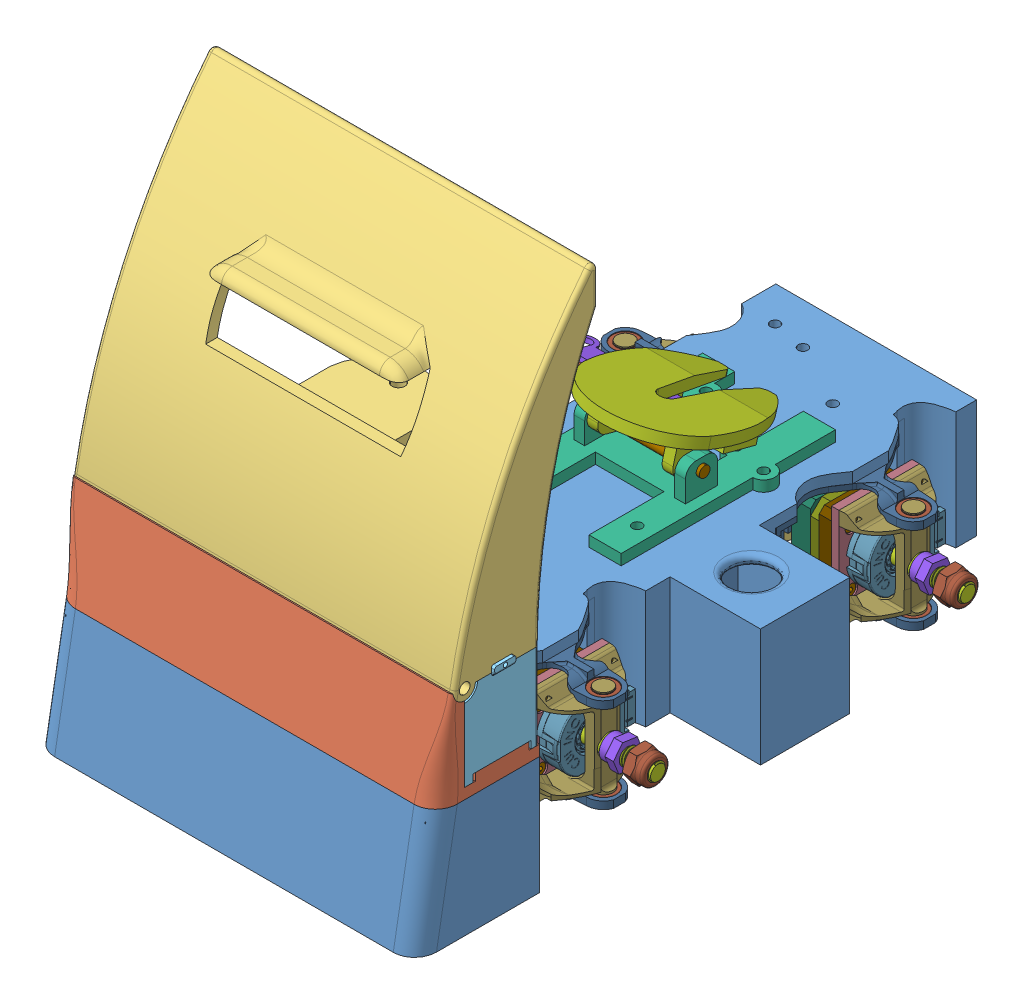
SolidWorks assembly Chassis assembly 3, configuration Default. Lengths in mm.
Overall size (185.37 241.94 304.3).
159 component instances, 30 part files, 30 mates.
Components (placement in the parent):
- Dolly chassis combined-2: Dolly chassis combined [Default] at (6.0852 69.6365 39.9835) x (1 0 0) z (0 1 0) size (178 304.3 55)
- front assembly 2-1: front assembly 2 [Default] at (-63.237 -3.2115 151.6894) size (181 187.95 83.28)
  - Foldable front base 2-1: Foldable front base 2 [Default] at (158.3211 77.8479 159.546) size (179.15 52.01 49.18)
  - foldable front flap 2-1: foldable front flap 2 [Default] at (69.3211 122.8479 151.0232) x (-1 0 0) z (0 0 -1) size (178.61 145.94 74.18)
  - Foldable front side flap right 2-1: Foldable front side flap right 2 [Default] at (-17.1789 86.3479 110.946) x (0 0 1) z (-1 0 0) size (35 43 8.5)
  - Foldable front side flap left 2-1: Foldable front side flap left 2 [Default] at (155.8211 86.3479 145.946) x (0 0 -1) z (1 0 0) size (35 43 8.5)
- Fifth_wheel_assembly-1: Fifth_wheel_assembly [Default] at (30.1809 28.8317 169.367) x (-1 0 0) z (0 0 -1) size (90.59 41.74 100)
  - Fifth_wheel_mount-1: Fifth_wheel_mount [Default] at (-6.9031 48.3048 102.7348) size (67.09 20 100)
  - Fifth_wheel_disk-1: Fifth_wheel_disk [Default] at (-5.9031 71.3457 44.4932) x (1 0 0) z (0 -0.255937 0.966694) size (66.74 23.06 75.99)
  - Fifth_wheel_kingpin-1: Fifth_wheel_kingpin [Default] at (-1.4031 62.5809 65.8769) x (1 0 0) z (0 -0.255937 0.966694) size (80 2 20)
  - Fifth_wheel_axle-1: Fifth_wheel_axle [Default] at (51.5969 60.8048 45.2348) x (0 0.948415 -0.31703) z (1 0 0) size (5 5 55)
- Module Assembly-2: Module Assembly [Default] at (72.5852 42.1365 211.1335) x (0 0 -1) z (1 0 0) size (68.25 51.28 97.81)
  - Housing-1: Housing [Default] at origin size (64.25 48.5 67.91)
  - Bearing 12x8-1: Bearing 12x8 [Default] at (0 -18.25 0.75) x (-0.914388 0 0.40484) z (-0.40484 0 -0.914388) size (12 3.5 12)
  - Spindle-1: Spindle [Default] at (0 2 0.75) size (49.04 45 20.5)
  - Spindle base-1: Spindle base [Default] at (0 2 -15.25) x (-1 0 0) z (0 -1 0) size (37.62 3.5 44.8)
  - Encoder-1: Encoder [Défaut] at (0 2 -12.48) x (0 1 0) z (0 0 1) size (28.68 37.25 10.4)
  - Wheel-1: Wheel [Default] at (0 2 -8.55) x (0.929787 0.368098 0) z (0.368098 -0.929787 0) size (81.5 31 81.5) (hidden)
  - Stepper Nema14-1: Stepper Nema14 [Predeterminado] at (4.764 -15.5 -30.1157) x (-1 0 0) z (0 1 0) size (37.8 40 35)
    - nema14_base-1: nema14_base [Predeterminado] at (-12.736 -8.6343 35) size (37.8 9 35)
    - nema14_centro-1: nema14_centro [Predeterminado] at (-12.736 0.3657 35) size (35 4 35)
    - nema14_eje-1: nema14_eje [Predeterminado] at (4.764 -6.6343 17.5) x (0 1 0) z (-0.939004 0 0.343907) size (38 5 5)
    - nema14_techo-1: nema14_techo [Predeterminado] at (-12.736 4.3657 35) size (35 9 35)
  - Servo motor-1: Servo motor [Default] at (-25.7048 26.288 -66.0832) x (0 0 1) z (1 0 0) size (11.5 29.2 32.5) (flexible)
    - TowerPro-SG90-Body-1: TowerPro-SG90-Body [Default] at (13.6721 7.288 30.7048) size (11.5 26 32.5)
    - ServoFinalGear-1: ServoFinalGear [Default] at (13.6721 33.288 25.7048) x (0.607544 0 -0.794286) z (0.794286 0 0.607544) size (4.64 3.2 4.64)
  - Control arm-1: Control arm [Default] at (0 -7.5 -52.4111) x (0.891007 0 0.45399) z (0.45399 0 -0.891007) size (37.9 4.5 7.8)
  - Ball joint assy-1: Ball joint assy [Default] at (-26.7302 -5 -12.8697) x (-0.874356 0 0.485286) z (0.485286 0 0.874356) size (15.43 16.21 22.24) (flexible)
    - Ball-1: Ball [Default] at origin size (5.5 15.11 5.5)
    - Joint-1: Joint [Default] at (-3.8823 13.66 -6.9948) x (0.874356 0 -0.485286) z (0 -1 0) size (5.1 22.6 5.1)
  - Ball joint assy-2: Ball joint assy [Default] at (-26.7302 -5 -66.0308) x (-0.846813 0 0.531891) z (0.531891 0 0.846813) size (16.34 16.21 21.85) (flexible)
    - Ball-1: Ball [Default] at origin size (5.5 15.11 5.5)
    - Joint-1: Joint [Default] at (4.2551 13.66 6.7745) x (-0.846813 0 0.531891) z (0 -1 0) size (5.1 22.6 5.1)
  - Steering rod-1: Steering rod [Default] at (-26.7302 -18.66 -18.4608) x (-0.014502 0.999895 0) z (-0.999895 -0.014502 0) size (3 28.27 3)
  - Wheel adapter-1: Wheel adapter [Default] at (0 2 -13.8175) x (0.291296 -0.956633 0) z (-0.956633 -0.291296 0) size (8.34 40 8.37)
  - Wheel spacer-1: Wheel spacer [Default] at (0 2 12.25) x (0.368098 -0.929787 0) z (0.929787 0.368098 0) size (13.86 8 12)
  - M3x5 din 7984-1: M3x5 din 7984 [Default] at (15.31 20.9 -16.25) x (0.933505 0.358563 0) z (0 0 -1) size (5.5 5.5 7)
  - Housing lid-1: Housing lid [Default] at (0 4 0) x (-1 0 0) z (0 0 1) size (68.25 9.28 69.91)
  - Bearing 12x8-3: Bearing 12x8 [Default] at (0 22.25 0.75) x (-0.914388 0 0.40484) z (0.40484 0 0.914388) size (12 3.5 12)
  - M8 nut-1: M8 nut [Default] at (0 2 16.6825) x (-0.817347 -0.576146 0) z (0 0 1) size (13 16.06 8.5)
  - M3x5 din 7984-2: M3x5 din 7984 [Default] at (15.31 -16.9 -16.25) x (-0.933505 0.358563 0) z (0 0 -1) size (5.5 5.5 7)
  - M3x5 din 7984-3: M3x5 din 7984 [Default] at (-15.31 20.9 -16.25) x (0.933505 -0.358563 0) z (0 0 -1) size (5.5 5.5 7)
  - M3x5 din 7984-4: M3x5 din 7984 [Default] at (-15.31 -16.9 -16.25) x (-0.933505 -0.358563 0) z (0 0 -1) size (5.5 5.5 7)
  - M3x5 din 7984-5: M3x5 din 7984 [Default] at (-13 15 -17.75) x (0.999849 0.017374 0) z (0 0 1) size (5.5 5.5 7)
  - M3x5 din 7984-6: M3x5 din 7984 [Default] at (-13 -11 -17.75) x (-0.999849 0.017374 0) z (0 0 1) size (5.5 5.5 7)
  - M3x5 din 7984-7: M3x5 din 7984 [Default] at (13 15 -17.75) x (0.999849 -0.017374 0) z (0 0 1) size (5.5 5.5 7)
  - M3x5 din 7984-8: M3x5 din 7984 [Default] at (13 -11 -17.75) x (-0.999849 -0.017374 0) z (0 0 1) size (5.5 5.5 7)
- Module Assembly-3: Module Assembly [Default] at (72.5852 42.1365 66.4835) x (0 0 -1) z (1 0 0) size (68.25 51.28 97.81)
  - Housing-1: Housing [Default] at origin size (64.25 48.5 67.91)
  - Bearing 12x8-1: Bearing 12x8 [Default] at (0 -18.25 0.75) x (-0.914388 0 0.40484) z (-0.40484 0 -0.914388) size (12 3.5 12)
  - Spindle-1: Spindle [Default] at (0 2 0.75) size (49.04 45 20.5)
  - Spindle base-1: Spindle base [Default] at (0 2 -15.25) x (-1 0 0) z (0 -1 0) size (37.62 3.5 44.8)
  - Encoder-1: Encoder [Défaut] at (0 2 -12.48) x (0 1 0) z (0 0 1) size (28.68 37.25 10.4)
  - Wheel-1: Wheel [Default] at (0 2 -8.55) x (0.929787 0.368098 0) z (0.368098 -0.929787 0) size (81.5 31 81.5) (hidden)
  - Stepper Nema14-1: Stepper Nema14 [Predeterminado] at (4.764 -15.5 -30.1157) x (-1 0 0) z (0 1 0) size (37.8 40 35)
    - nema14_base-1: nema14_base [Predeterminado] at (-12.736 -8.6343 35) size (37.8 9 35)
    - nema14_centro-1: nema14_centro [Predeterminado] at (-12.736 0.3657 35) size (35 4 35)
    - nema14_eje-1: nema14_eje [Predeterminado] at (4.764 -6.6343 17.5) x (0 1 0) z (-0.939004 0 0.343907) size (38 5 5)
    - nema14_techo-1: nema14_techo [Predeterminado] at (-12.736 4.3657 35) size (35 9 35)
  - Servo motor-1: Servo motor [Default] at (-25.7048 26.288 -66.0832) x (0 0 1) z (1 0 0) size (11.5 29.2 32.5) (flexible)
    - TowerPro-SG90-Body-1: TowerPro-SG90-Body [Default] at (13.6721 7.288 30.7048) size (11.5 26 32.5)
    - ServoFinalGear-1: ServoFinalGear [Default] at (13.6721 33.288 25.7048) x (0.607544 0 -0.794286) z (0.794286 0 0.607544) size (4.64 3.2 4.64)
  - Control arm-1: Control arm [Default] at (0 -7.5 -52.4111) x (0.891007 0 0.45399) z (0.45399 0 -0.891007) size (37.9 4.5 7.8)
  - Ball joint assy-1: Ball joint assy [Default] at (-26.7302 -5 -12.8697) x (-0.874356 0 0.485286) z (0.485286 0 0.874356) size (15.43 16.21 22.24) (flexible)
    - Ball-1: Ball [Default] at origin size (5.5 15.11 5.5)
    - Joint-1: Joint [Default] at (-3.8823 13.66 -6.9948) x (0.874356 0 -0.485286) z (0 -1 0) size (5.1 22.6 5.1)
  - Ball joint assy-2: Ball joint assy [Default] at (-26.7302 -5 -66.0308) x (-0.846813 0 0.531891) z (0.531891 0 0.846813) size (16.34 16.21 21.85) (flexible)
    - Ball-1: Ball [Default] at origin size (5.5 15.11 5.5)
    - Joint-1: Joint [Default] at (4.2551 13.66 6.7745) x (-0.846813 0 0.531891) z (0 -1 0) size (5.1 22.6 5.1)
  - Steering rod-1: Steering rod [Default] at (-26.7302 -18.66 -18.4608) x (-0.014502 0.999895 0) z (-0.999895 -0.014502 0) size (3 28.27 3)
  - Wheel adapter-1: Wheel adapter [Default] at (0 2 -13.8175) x (0.291296 -0.956633 0) z (-0.956633 -0.291296 0) size (8.34 40 8.37)
  - Wheel spacer-1: Wheel spacer [Default] at (0 2 12.25) x (0.368098 -0.929787 0) z (0.929787 0.368098 0) size (13.86 8 12)
  - M3x5 din 7984-1: M3x5 din 7984 [Default] at (15.31 20.9 -16.25) x (0.933505 0.358563 0) z (0 0 -1) size (5.5 5.5 7)
  - Housing lid-1: Housing lid [Default] at (0 4 0) x (-1 0 0) z (0 0 1) size (68.25 9.28 69.91)
  - Bearing 12x8-3: Bearing 12x8 [Default] at (0 22.25 0.75) x (-0.914388 0 0.40484) z (0.40484 0 0.914388) size (12 3.5 12)
  - M8 nut-1: M8 nut [Default] at (0 2 16.6825) x (-0.817347 -0.576146 0) z (0 0 1) size (13 16.06 8.5)
  - M3x5 din 7984-2: M3x5 din 7984 [Default] at (15.31 -16.9 -16.25) x (-0.933505 0.358563 0) z (0 0 -1) size (5.5 5.5 7)
  - M3x5 din 7984-3: M3x5 din 7984 [Default] at (-15.31 20.9 -16.25) x (0.933505 -0.358563 0) z (0 0 -1) size (5.5 5.5 7)
  - M3x5 din 7984-4: M3x5 din 7984 [Default] at (-15.31 -16.9 -16.25) x (-0.933505 -0.358563 0) z (0 0 -1) size (5.5 5.5 7)
  - M3x5 din 7984-5: M3x5 din 7984 [Default] at (-13 15 -17.75) x (0.999849 0.017374 0) z (0 0 1) size (5.5 5.5 7)
  - M3x5 din 7984-6: M3x5 din 7984 [Default] at (-13 -11 -17.75) x (-0.999849 0.017374 0) z (0 0 1) size (5.5 5.5 7)
  - M3x5 din 7984-7: M3x5 din 7984 [Default] at (13 15 -17.75) x (0.999849 -0.017374 0) z (0 0 1) size (5.5 5.5 7)
  - M3x5 din 7984-8: M3x5 din 7984 [Default] at (13 -11 -17.75) x (-0.999849 -0.017374 0) z (0 0 1) size (5.5 5.5 7)
- Module Assembly-4: Module Assembly [Default] at (-60.4148 42.1365 211.1335) x (0 0 1) z (-1 0 0) size (68.25 51.28 97.81)
  - Housing-1: Housing [Default] at origin size (64.25 48.5 67.91)
  - Bearing 12x8-1: Bearing 12x8 [Default] at (0 -18.25 0.75) x (-0.914388 0 0.40484) z (-0.40484 0 -0.914388) size (12 3.5 12)
  - Spindle-1: Spindle [Default] at (0 2 0.75) size (49.04 45 20.5)
  - Spindle base-1: Spindle base [Default] at (0 2 -15.25) x (-1 0 0) z (0 -1 0) size (37.62 3.5 44.8)
  - Encoder-1: Encoder [Défaut] at (0 2 -12.48) x (0 1 0) z (0 0 1) size (28.68 37.25 10.4)
  - Wheel-1: Wheel [Default] at (0 2 -8.55) x (0.929787 0.368098 0) z (0.368098 -0.929787 0) size (81.5 31 81.5) (hidden)
  - Stepper Nema14-1: Stepper Nema14 [Predeterminado] at (4.764 -15.5 -30.1157) x (-1 0 0) z (0 1 0) size (37.8 40 35)
    - nema14_base-1: nema14_base [Predeterminado] at (-12.736 -8.6343 35) size (37.8 9 35)
    - nema14_centro-1: nema14_centro [Predeterminado] at (-12.736 0.3657 35) size (35 4 35)
    - nema14_eje-1: nema14_eje [Predeterminado] at (4.764 -6.6343 17.5) x (0 1 0) z (-0.939004 0 0.343907) size (38 5 5)
    - nema14_techo-1: nema14_techo [Predeterminado] at (-12.736 4.3657 35) size (35 9 35)
  - Servo motor-1: Servo motor [Default] at (-25.7048 26.288 -66.0832) x (0 0 1) z (1 0 0) size (11.5 29.2 32.5) (flexible)
    - TowerPro-SG90-Body-1: TowerPro-SG90-Body [Default] at (13.6721 7.288 30.7048) size (11.5 26 32.5)
    - ServoFinalGear-1: ServoFinalGear [Default] at (13.6721 33.288 25.7048) x (0.607544 0 -0.794286) z (0.794286 0 0.607544) size (4.64 3.2 4.64)
  - Control arm-1: Control arm [Default] at (0 -7.5 -52.4111) x (0.891007 0 0.45399) z (0.45399 0 -0.891007) size (37.9 4.5 7.8)
  - Ball joint assy-1: Ball joint assy [Default] at (-26.7302 -5 -12.8697) x (-0.874356 0 0.485286) z (0.485286 0 0.874356) size (15.43 16.21 22.24) (flexible)
    - Ball-1: Ball [Default] at origin size (5.5 15.11 5.5)
    - Joint-1: Joint [Default] at (-3.8823 13.66 -6.9948) x (0.874356 0 -0.485286) z (0 -1 0) size (5.1 22.6 5.1)
  - Ball joint assy-2: Ball joint assy [Default] at (-26.7302 -5 -66.0308) x (-0.846813 0 0.531891) z (0.531891 0 0.846813) size (16.34 16.21 21.85) (flexible)
    - Ball-1: Ball [Default] at origin size (5.5 15.11 5.5)
    - Joint-1: Joint [Default] at (4.2551 13.66 6.7745) x (-0.846813 0 0.531891) z (0 -1 0) size (5.1 22.6 5.1)
  - Steering rod-1: Steering rod [Default] at (-26.7302 -18.66 -18.4608) x (-0.014502 0.999895 0) z (-0.999895 -0.014502 0) size (3 28.27 3)
  - Wheel adapter-1: Wheel adapter [Default] at (0 2 -13.8175) x (0.291296 -0.956633 0) z (-0.956633 -0.291296 0) size (8.34 40 8.37)
  - Wheel spacer-1: Wheel spacer [Default] at (0 2 12.25) x (0.368098 -0.929787 0) z (0.929787 0.368098 0) size (13.86 8 12)
  - M3x5 din 7984-1: M3x5 din 7984 [Default] at (15.31 20.9 -16.25) x (0.933505 0.358563 0) z (0 0 -1) size (5.5 5.5 7)
  - Housing lid-1: Housing lid [Default] at (0 4 0) x (-1 0 0) z (0 0 1) size (68.25 9.28 69.91)
  - Bearing 12x8-3: Bearing 12x8 [Default] at (0 22.25 0.75) x (-0.914388 0 0.40484) z (0.40484 0 0.914388) size (12 3.5 12)
  - M8 nut-1: M8 nut [Default] at (0 2 16.6825) x (-0.817347 -0.576146 0) z (0 0 1) size (13 16.06 8.5)
  - M3x5 din 7984-2: M3x5 din 7984 [Default] at (15.31 -16.9 -16.25) x (-0.933505 0.358563 0) z (0 0 -1) size (5.5 5.5 7)
  - M3x5 din 7984-3: M3x5 din 7984 [Default] at (-15.31 20.9 -16.25) x (0.933505 -0.358563 0) z (0 0 -1) size (5.5 5.5 7)
  - M3x5 din 7984-4: M3x5 din 7984 [Default] at (-15.31 -16.9 -16.25) x (-0.933505 -0.358563 0) z (0 0 -1) size (5.5 5.5 7)
  - M3x5 din 7984-5: M3x5 din 7984 [Default] at (-13 15 -17.75) x (0.999849 0.017374 0) z (0 0 1) size (5.5 5.5 7)
  - M3x5 din 7984-6: M3x5 din 7984 [Default] at (-13 -11 -17.75) x (-0.999849 0.017374 0) z (0 0 1) size (5.5 5.5 7)
  - M3x5 din 7984-7: M3x5 din 7984 [Default] at (13 15 -17.75) x (0.999849 -0.017374 0) z (0 0 1) size (5.5 5.5 7)
  - M3x5 din 7984-8: M3x5 din 7984 [Default] at (13 -11 -17.75) x (-0.999849 -0.017374 0) z (0 0 1) size (5.5 5.5 7)
- Module Assembly-5: Module Assembly [Default] at (-60.4148 42.1365 66.4835) x (0 0 1) z (-1 0 0) size (68.25 51.28 97.81)
  - Housing-1: Housing [Default] at origin size (64.25 48.5 67.91)
  - Bearing 12x8-1: Bearing 12x8 [Default] at (0 -18.25 0.75) x (-0.914388 0 0.40484) z (-0.40484 0 -0.914388) size (12 3.5 12)
  - Spindle-1: Spindle [Default] at (0 2 0.75) size (49.04 45 20.5)
  - Spindle base-1: Spindle base [Default] at (0 2 -15.25) x (-1 0 0) z (0 -1 0) size (37.62 3.5 44.8)
  - Encoder-1: Encoder [Défaut] at (0 2 -12.48) x (0 1 0) z (0 0 1) size (28.68 37.25 10.4)
  - Wheel-1: Wheel [Default] at (0 2 -8.55) x (0.929787 0.368098 0) z (0.368098 -0.929787 0) size (81.5 31 81.5) (hidden)
  - Stepper Nema14-1: Stepper Nema14 [Predeterminado] at (4.764 -15.5 -30.1157) x (-1 0 0) z (0 1 0) size (37.8 40 35)
    - nema14_base-1: nema14_base [Predeterminado] at (-12.736 -8.6343 35) size (37.8 9 35)
    - nema14_centro-1: nema14_centro [Predeterminado] at (-12.736 0.3657 35) size (35 4 35)
    - nema14_eje-1: nema14_eje [Predeterminado] at (4.764 -6.6343 17.5) x (0 1 0) z (-0.939004 0 0.343907) size (38 5 5)
    - nema14_techo-1: nema14_techo [Predeterminado] at (-12.736 4.3657 35) size (35 9 35)
  - Servo motor-1: Servo motor [Default] at (-25.7048 26.288 -66.0832) x (0 0 1) z (1 0 0) size (11.5 29.2 32.5) (flexible)
    - TowerPro-SG90-Body-1: TowerPro-SG90-Body [Default] at (13.6721 7.288 30.7048) size (11.5 26 32.5)
    - ServoFinalGear-1: ServoFinalGear [Default] at (13.6721 33.288 25.7048) x (0.607544 0 -0.794286) z (0.794286 0 0.607544) size (4.64 3.2 4.64)
  - Control arm-1: Control arm [Default] at (0 -7.5 -52.4111) x (0.891007 0 0.45399) z (0.45399 0 -0.891007) size (37.9 4.5 7.8)
  - Ball joint assy-1: Ball joint assy [Default] at (-26.7302 -5 -12.8697) x (-0.874356 0 0.485286) z (0.485286 0 0.874356) size (15.43 16.21 22.24) (flexible)
    - Ball-1: Ball [Default] at origin size (5.5 15.11 5.5)
    - Joint-1: Joint [Default] at (-3.8823 13.66 -6.9948) x (0.874356 0 -0.485286) z (0 -1 0) size (5.1 22.6 5.1)
  - Ball joint assy-2: Ball joint assy [Default] at (-26.7302 -5 -66.0308) x (-0.846813 0 0.531891) z (0.531891 0 0.846813) size (16.34 16.21 21.85) (flexible)
    - Ball-1: Ball [Default] at origin size (5.5 15.11 5.5)
    - Joint-1: Joint [Default] at (4.2551 13.66 6.7745) x (-0.846813 0 0.531891) z (0 -1 0) size (5.1 22.6 5.1)
  - Steering rod-1: Steering rod [Default] at (-26.7302 -18.66 -18.4608) x (-0.014502 0.999895 0) z (-0.999895 -0.014502 0) size (3 28.27 3)
  - Wheel adapter-1: Wheel adapter [Default] at (0 2 -13.8175) x (0.291296 -0.956633 0) z (-0.956633 -0.291296 0) size (8.34 40 8.37)
  - Wheel spacer-1: Wheel spacer [Default] at (0 2 12.25) x (0.368098 -0.929787 0) z (0.929787 0.368098 0) size (13.86 8 12)
  - M3x5 din 7984-1: M3x5 din 7984 [Default] at (15.31 20.9 -16.25) x (0.933505 0.358563 0) z (0 0 -1) size (5.5 5.5 7)
  - Housing lid-1: Housing lid [Default] at (0 4 0) x (-1 0 0) z (0 0 1) size (68.25 9.28 69.91)
  - Bearing 12x8-3: Bearing 12x8 [Default] at (0 22.25 0.75) x (-0.914388 0 0.40484) z (0.40484 0 0.914388) size (12 3.5 12)
  - M8 nut-1: M8 nut [Default] at (0 2 16.6825) x (-0.817347 -0.576146 0) z (0 0 1) size (13 16.06 8.5)
  - M3x5 din 7984-2: M3x5 din 7984 [Default] at (15.31 -16.9 -16.25) x (-0.933505 0.358563 0) z (0 0 -1) size (5.5 5.5 7)
  - M3x5 din 7984-3: M3x5 din 7984 [Default] at (-15.31 20.9 -16.25) x (0.933505 -0.358563 0) z (0 0 -1) size (5.5 5.5 7)
  - M3x5 din 7984-4: M3x5 din 7984 [Default] at (-15.31 -16.9 -16.25) x (-0.933505 -0.358563 0) z (0 0 -1) size (5.5 5.5 7)
  - M3x5 din 7984-5: M3x5 din 7984 [Default] at (-13 15 -17.75) x (0.999849 0.017374 0) z (0 0 1) size (5.5 5.5 7)
  - M3x5 din 7984-6: M3x5 din 7984 [Default] at (-13 -11 -17.75) x (-0.999849 0.017374 0) z (0 0 1) size (5.5 5.5 7)
  - M3x5 din 7984-7: M3x5 din 7984 [Default] at (13 15 -17.75) x (0.999849 -0.017374 0) z (0 0 1) size (5.5 5.5 7)
  - M3x5 din 7984-8: M3x5 din 7984 [Default] at (13 -11 -17.75) x (-0.999849 -0.017374 0) z (0 0 1) size (5.5 5.5 7)
- Wheel-1: Wheel [Default] at (64.0352 44.1365 66.4835) x (0 0.62117 0.783676) z (0 0.783676 -0.62117) size (81.5 31 81.5) (hidden)
- Wheel-2: Wheel [Default] at (-51.8648 44.1365 66.4835) x (0 0.62117 -0.783676) z (0 0.783676 0.62117) size (81.5 31 81.5) (hidden)
- Wheel-3: Wheel [Default] at (-51.8648 44.1365 211.1335) x (0 0.62117 -0.783676) z (0 0.783676 0.62117) size (81.5 31 81.5) (hidden)
- Wheel-4: Wheel [Default] at (64.0352 44.1365 211.1335) x (0 0.62117 0.783676) z (0 0.783676 -0.62117) size (81.5 31 81.5) (hidden)
Mates (geometry in assembly coordinates):
- Coincident2: coincident: plane of Dolly chassis combined-2 through (6.0852 74.6365 39.9835) normal (0 1 0); plane of front assembly 2-1/Foldable front base 2-1 through (95.0841 74.6365 311.2355) normal (0 -1 0)
- Coincident3: coincident: plane of Dolly chassis combined-2 through (95.0841 69.6365 39.9835) normal (1 0 0); plane of front assembly 2-1/Foldable front base 2-1 through (95.0841 119.6365 311.2355) normal (1 0 0)
- Coincident4: coincident: plane of Dolly chassis combined-2 through (150.9325 19.6365 320.9335) normal (0 0.173648 0.984808); plane of front assembly 2-1/Foldable front base 2-1 through (95.0841 74.6365 311.2355) normal (0 0.173648 0.984808)
- Coincident5: coincident: plane of Dolly chassis combined-2 through (6.0852 74.6365 39.9835) normal (0 1 0); plane of Fifth_wheel_assembly-1/Fifth_wheel_mount-1 through (37.0841 74.6365 66.6321) normal (0 -1 0)
- Concentric1: concentric: cylinder of Dolly chassis combined-2 through (36.9241 74.6365 99.9835) axis (0 -1 0) radius 2.25; cylinder of Fifth_wheel_assembly-1/Fifth_wheel_mount-1 through (36.9241 62.3333 99.9835) axis (0 1 0) radius 2.25
- Concentric2: concentric: cylinder of Dolly chassis combined-2 through (29.5841 63.2725 151.6321) axis (0 1 0) radius 2.25; cylinder of Fifth_wheel_assembly-1/Fifth_wheel_mount-1 through (29.5841 74.6365 151.6321) axis (0 1 0) radius 2.25
- Coincident6: coincident: plane of Dolly chassis combined-2 through (6.0852 69.6365 39.9835) normal (0 -1 0); plane of Module Assembly-2/Housing lid-1 through (72.5852 69.6365 211.1335) normal (0 1 0)
- Concentric3: concentric: cylinder of Dolly chassis combined-2 through (36.9241 74.6365 244.6335) axis (0 -1 0) radius 2.25; cylinder of Module Assembly-2/Housing lid-1 through (36.9241 60.6365 244.6335) axis (0 1 0) radius 2.8
- Coincident7: coincident: plane of Dolly chassis combined-2 through (52.9241 74.6365 184.6335) normal (1 0 0); plane of Module Assembly-2/Housing lid-1 through (52.9241 67.1365 211.1335) normal (1 0 0)
- Coincident8: coincident: plane of Dolly chassis combined-2 through (6.0852 69.6365 39.9835) normal (0 -1 0); plane of Module Assembly-3/Housing lid-1 through (72.5852 69.6365 66.4835) normal (0 1 0)
- Concentric4: concentric: cylinder of Fifth_wheel_assembly-1/Fifth_wheel_mount-1 through (36.9241 62.3333 99.9835) axis (0 1 0) radius 2.25; cylinder of Module Assembly-3/Housing lid-1 through (36.9241 60.6365 99.9835) axis (0 1 0) radius 2.8
- Coincident9: coincident: plane of Dolly chassis combined-2 through (52.9241 74.6365 39.9835) normal (1 0 0); plane of Module Assembly-3/Housing lid-1 through (52.9241 67.1365 66.4835) normal (1 0 0)
- Coincident10: coincident: plane of Dolly chassis combined-2 through (6.0852 69.6365 39.9835) normal (0 -1 0); plane of Module Assembly-4/Housing lid-1 through (-60.4148 69.6365 211.1335) normal (0 1 0)
- Concentric5: concentric: cylinder of Dolly chassis combined-2 through (-8.7537 74.6365 225.8835) axis (0 -1 0) radius 2.25; cylinder of Module Assembly-4/Housing lid-1 through (-8.7537 61.3365 225.8835) axis (0 1 0) radius 2.8
- Coincident11: coincident: plane of Dolly chassis combined-2 through (-40.7537 74.6365 39.9835) normal (-1 0 0); plane of Module Assembly-4/Housing lid-1 through (-40.7537 67.1365 211.1335) normal (-1 0 0)
- Coincident12: coincident: plane of Dolly chassis combined-2 through (6.0852 69.6365 39.9835) normal (0 -1 0); plane of Module Assembly-5/Housing lid-1 through (-60.4148 69.6365 66.4835) normal (0 1 0)
- Concentric6: concentric: cylinder of Dolly chassis combined-2 through (-8.7537 74.6365 35.9835) axis (0 -1 0) radius 2.25; cylinder of Module Assembly-5/Housing lid-1 through (-8.7537 60.6365 35.9835) axis (0 1 0) radius 2.8
- Coincident13: coincident: plane of Dolly chassis combined-2 through (-40.7537 74.6365 39.9835) normal (-1 0 0); plane of Module Assembly-5/Housing lid-1 through (-40.7537 67.1365 66.4835) normal (-1 0 0)
- Concentric7: concentric: cylinder of Module Assembly-3/Wheel adapter-1 through (58.7677 44.1365 66.4835) axis (-1 0 0) radius 4; cylinder of Wheel-1 through (64.0352 44.1365 66.4835) axis (1 0 0) radius 4
- Coincident14: coincident: plane of Module Assembly-3/Wheel spacer-1 through (76.8352 49.5659 62.1799) normal (0 0.368098 -0.929787); plane of Wheel-1 through (84.8352 49.5659 62.1799) normal (0 -0.368098 0.929787)
- Coincident15: coincident: plane of Module Assembly-3/Wheel spacer-1 through (84.8352 44.1365 66.4835) normal (1 0 0); plane of Wheel-1 through (84.8352 44.1365 66.4835) normal (-1 0 0)
- Concentric8: concentric: cylinder of Module Assembly-5/Wheel adapter-1 through (-46.5973 44.1365 66.4835) axis (1 0 0) radius 4; cylinder of Wheel-2 through (-51.8648 44.1365 66.4835) axis (-1 0 0) radius 4
- Coincident16: coincident: plane of Module Assembly-5/Wheel spacer-1 through (-64.6648 50.5782 63.9332) normal (0 0.989268 0.146111); plane of Wheel-2 through (-72.6648 50.5782 63.9332) normal (0 -0.989268 -0.146111)
- Coincident17: coincident: plane of Module Assembly-5/Wheel spacer-1 through (-72.6648 44.1365 66.4835) normal (-1 0 0); plane of Wheel-2 through (-72.6648 44.1365 66.4835) normal (1 0 0)
- Coincident18: coincident: plane of Module Assembly-4/Wheel spacer-1 through (-64.6648 50.5782 208.5832) normal (0 0.989268 0.146111); plane of Wheel-3 through (-72.6648 50.5782 208.5832) normal (0 -0.989268 -0.146111)
- Concentric9: concentric: cylinder of Module Assembly-4/Wheel adapter-1 through (-46.5973 44.1365 211.1335) axis (1 0 0) radius 4; cylinder of Wheel-3 through (-51.8648 44.1365 211.1335) axis (-1 0 0) radius 4
- Coincident19: coincident: plane of Module Assembly-4/Wheel spacer-1 through (-72.6648 44.1365 211.1335) normal (-1 0 0); plane of Wheel-3 through (-72.6648 44.1365 211.1335) normal (1 0 0)
- Concentric10: concentric: cylinder of Module Assembly-2/Wheel adapter-1 through (58.7677 44.1365 211.1335) axis (-1 0 0) radius 4; cylinder of Wheel-4 through (64.0352 44.1365 211.1335) axis (1 0 0) radius 4
- Coincident20: coincident: plane of Module Assembly-2/Wheel spacer-1 through (76.8352 49.5659 206.8299) normal (0 0.368098 -0.929787); plane of Wheel-4 through (84.8352 49.5659 206.8299) normal (0 -0.368098 0.929787)
- Coincident21: coincident: plane of Module Assembly-2/Wheel spacer-1 through (84.8352 44.1365 211.1335) normal (1 0 0); plane of Wheel-4 through (84.8352 44.1365 211.1335) normal (-1 0 0)
